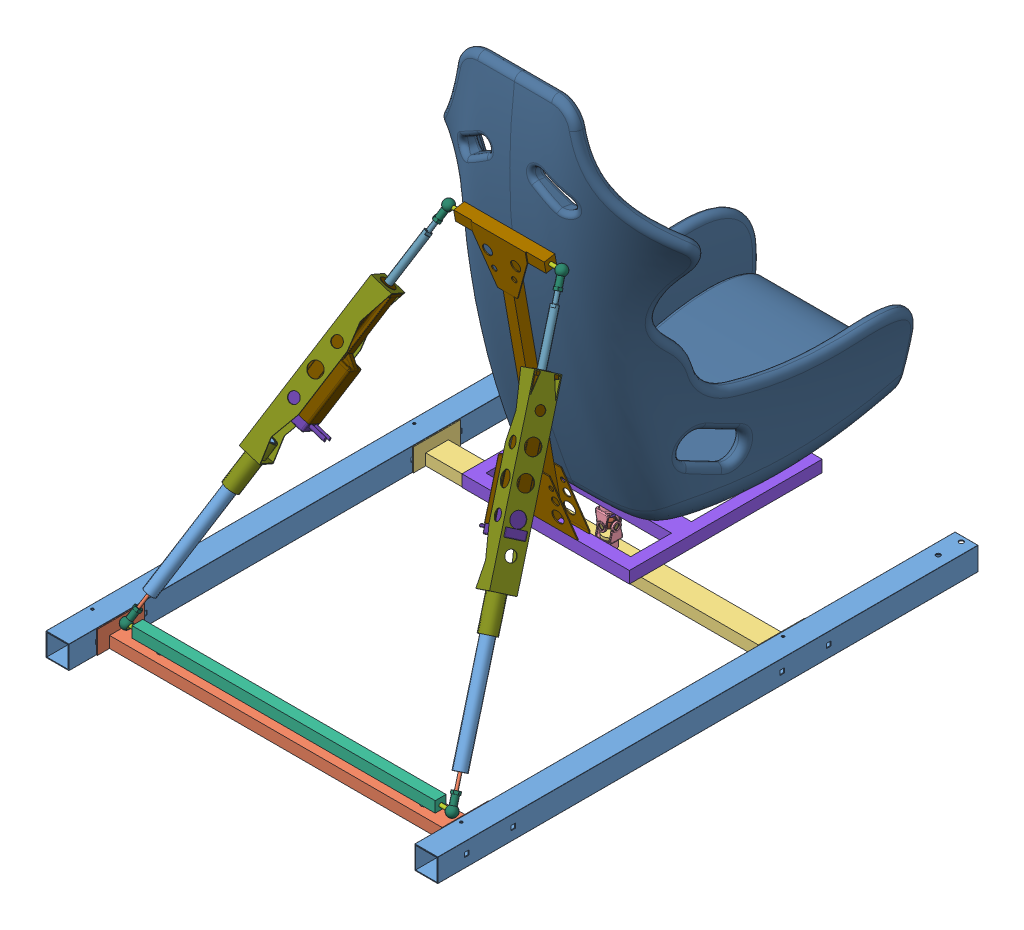
SolidWorks assembly simulateur, configuration Défaut. Lengths in mm.
Overall size (866 1108.83 1485.74).
50 component instances, 20 part files, 13 mates.
Components (placement in the parent):
- chassis-1: chassis [Défaut] at origin size (866 78.98 1194)
  - chassis_barre_laterale-1: chassis_barre_laterale [Défaut] at (-24.4445 -23.571 0) size (51 51 1194)
  - chassis_barre_laterale-2: chassis_barre_laterale [Défaut] at (-839.4445 -23.571 0) size (51 51 1194)
  - barre_arriere-1: barre_arriere [Défaut] at (-786.4445 -23.571 1056.3322) x (0 1 0) z (1 0 0) size (50 104 764)
  - barre_centrale-1: barre_centrale [Défaut] at (-26.4445 -23.571 407.634) x (0 1 0) z (-1 0 0) size (50 104 764)
  - fourche-1: fourche [Défaut] at (-406.4445 -20.721 382.634) x (0 0 1) z (-1 0 0) size (30.18 53.98 36.51)
  - plot-1: plot [Défaut] at (-696.9445 1.429 1081.4017) x (0 1 0) z (0 0 1) size (10 15 15)
  - plot-2: plot [Défaut] at (-115.9445 1.429 1081.4763) x (0 1 0) z (-0.196557 0 0.980492) size (10 15 15)
  - barre-1: barre [Défaut] at (-746.4445 35.429 1096.7272) x (0 0 -1) z (0 -1 0) size (24 670 24)
  - joint_rotule_male-1: joint_rotule_male [Défaut] at (-771.4445 21.1645 1084.3239) x (0 0.466315 -0.884619) z (1 0 0) size (20 20 35)
  - joint_rotule_male-2: joint_rotule_male [Défaut] at (-51.4445 21.1645 1084.3239) x (0 0.99969 0.0249) z (-1 0 0) size (20 20 35)
- siege-1: siege [Défaut] at (-246.4445 90.329 96.634) x (0 0 1) z (0 1 0) size (1024.11 731.48 1108.83)
  - support_siege_inferieur-1: support_siege_inferieur [Défaut] at origin size (426 370 52)
  - support_siege_arriere-1: support_siege_arriere [Défaut] at (424.1282 -171.5 26.7272) x (0.173648 0 0.984808) z (-0.984808 0 0.173648) size (636.1 200 32.48)
  - fourche-1: fourche [Défaut] at (286 -160 22.15) x (0 1 0) z (-1 0 0) size (30.18 53.98 36.51)
  - siege-1: siege [Défaut] at (-162.8445 -147.6332 -30.6502) x (-0.014699 -0.999786 -0.014541) z (-0.988338 0.016732 -0.151352) size (705.1 977.38 875.83)
  - joint_rotule_male-1: joint_rotule_male [Défaut] at (515.8074 -284.5 615.7706) x (-0.898781 0 0.438397) z (0 1 0) size (20 20 35)
  - joint_rotule_male-2: joint_rotule_male [Défaut] at (515.8074 -34.5 615.7706) x (0.795824 0 -0.605528) z (0 -1 0) size (20 20 35)
- joint_croix-1: joint_croix [Défaut] at (-406.4445 45.879 382.6338) x (0 0 -1) z (1 0 0) size (31.75 17.28 31.75)
  - croix-1: croix [Défaut] at origin size (28.57 12.7 28.57)
  - coussinet-1: coussinet [Défaut] at (-8.501 0 0) x (0 0.97948 0.20154) z (-1 0 0) size (12.7 12.7 3.97)
  - coussinet-2: coussinet [Défaut] at (-0.0002 0 -8.5008) x (0.94577 -0.324837 0) z (0 0 -1) size (12.7 12.7 3.97)
  - coussinet-3: coussinet [Défaut] at (-0.0002 0 8.5008) size (12.7 12.7 3.97)
  - coussinet-4: coussinet [Défaut] at (8.5006 0 0) x (0 -0.488169 -0.872749) z (1 0 0) size (12.7 12.7 3.97)
  - snapring-1: snapring [Défaut] at (15.4779 -0.0149 -0.2115) x (0 -0.997523 0.070347) z (1 0 0) size (14.29 14.21 0.79)
  - snapring-2: snapring [Défaut] at (-0.0002 0.212 -15.4781) size (14.29 14.21 0.79)
  - snapring-3: snapring [Défaut] at (-0.0002 0.212 15.4781) size (14.29 14.21 0.79)
  - snapring-4: snapring [Défaut] at (-15.4783 0.2076 -0.0428) x (0 -0.201908 -0.979404) z (1 0 0) size (14.29 14.21 0.79)
- tige_verin-1: tige_verin [Défaut] at (-606.3592 491.3214 760.4117) x (-0.960475 0.239444 -0.141964) z (0.27777 0.79108 -0.54501) size (25.18 26.83 230.5)
  - tige_verin-1: tige_verin [Défaut] at origin size (15 15 186.5)
  - joint_rotule_femelle-1: joint_rotule_femelle [Défaut] at (0 0 271.5) x (-0.954092 -0.299513 0) z (0 0 -1) size (19.49 22 44)
- verin-1: verin [Défaut] at (-700.8199 295.8158 874.9491) x (0.27777 0.79108 -0.54501) z (0.930808 -0.36194 -0.050958) size (715 50 102.68)
  - support_verin-1: support_verin [Défaut] at origin size (422 50 46)
  - corps_verin-1: corps_verin [Défaut] at (53.4998 119.4835 -2.1976) x (0 1 0) z (1 0 0) size (45 102.68 269)
    - RSA04-1: RSA04 [Défaut] at (-95.9835 24.6976 97.5002) size (44 102.68 87.5)
    - prt-SCN5-150-2: prt-SCN5-150 [Défaut] at (-96.4835 25.1976 97.5002) size (45 68.14 252)
  - extension_tige-1: extension_tige [Défaut] at (32 23 23) x (0 -0.760787 -0.649002) z (-1 0 0) size (26 26 320)
  - joint_rotule_femelle-1: joint_rotule_femelle [Défaut] at (-351 23 23) x (0 0.07072 0.997496) z (1 0 0) size (19.49 22 44)
  - tige_filetee-1: tige_filetee [Défaut] at (-172 23 23) x (0 -0.855363 -0.518028) z (0 0.518028 -0.855363) size (6 152 6)
- tige_verin-2: tige_verin [Défaut] at (-208.7297 490.577 760.9246) x (0.450435 0.603939 0.657546) z (-0.265985 0.793822 -0.5469) size (25.18 26.83 230.5)
  - tige_verin-1: tige_verin [Défaut] at origin size (15 15 186.5)
  - joint_rotule_femelle-1: joint_rotule_femelle [Défaut] at (0 0 271.5) x (-0.954092 -0.299513 0) z (0 0 -1) size (19.49 22 44)
- verin-2: verin [Défaut] at (-134.1225 319.573 915.8729) x (-0.265985 0.793822 -0.5469) z (-0.873086 -0.438873 -0.212396) size (715 50 102.68)
  - support_verin-1: support_verin [Défaut] at origin size (422 50 46)
  - corps_verin-1: corps_verin [Défaut] at (53.4998 119.4835 -2.1976) x (0 1 0) z (1 0 0) size (45 102.68 269)
    - RSA04-1: RSA04 [Défaut] at (-95.9835 24.6976 97.5002) size (44 102.68 87.5)
    - prt-SCN5-150-2: prt-SCN5-150 [Défaut] at (-96.4835 25.1976 97.5002) size (45 68.14 252)
  - extension_tige-1: extension_tige [Défaut] at (32 23 23) x (0 -0.760787 -0.649002) z (-1 0 0) size (26 26 320)
  - joint_rotule_femelle-1: joint_rotule_femelle [Défaut] at (-351 23 23) x (0 0.07072 0.997496) z (1 0 0) size (19.49 22 44)
  - tige_filetee-1: tige_filetee [Défaut] at (-172 23 23) x (0 -0.855363 -0.518028) z (0 0.518028 -0.855363) size (6 152 6)
Mates (geometry in assembly coordinates):
- Coaxiale1: concentric anti-aligned: cylinder of chassis-1/fourche-1; cylinder of joint_croix-1/coussinet-2
- Coaxiale2: concentric anti-aligned: cylinder of chassis-1/fourche-1; cylinder of joint_croix-1/coussinet-2
- Coïncidente1: coincident anti-aligned: plane of chassis-1/fourche-1 through (-422.3195 45.879 382.634) normal (1 0 0); plane of joint_croix-1/snapring-2 through (-422.3195 45.879 382.634) normal (-1 0 0)
- Coaxiale3: concentric anti-aligned: cylinder of siege-1/fourche-1; cylinder of joint_croix-1/coussinet-1
- Coïncidente2: coincident anti-aligned: plane of siege-1/fourche-1 through (-406.4445 45.879 398.509) normal (0 0 -1); plane of joint_croix-1/snapring-4 through (-406.4445 45.879 398.509) normal (0 0 1)
- Coaxiale4: concentric anti-aligned: cylinder of tige_verin-1/tige_verin-1; cylinder of verin-1/corps_verin-1/prt-SCN5-150-2
- Coaxiale5: concentric: sphere of siege-1/joint_rotule_male-1; sphere of tige_verin-1/joint_rotule_femelle-1
- Coaxiale6: concentric: sphere of siege-1/joint_rotule_male-2; sphere of tige_verin-2/joint_rotule_femelle-1
- Coaxiale7: concentric anti-aligned: cylinder of tige_verin-2/tige_verin-1; cylinder of verin-2/corps_verin-1/prt-SCN5-150-2
- Coaxiale8: concentric: sphere of chassis-1/joint_rotule_male-1; sphere of verin-1/joint_rotule_femelle-1
- Coaxiale9: concentric: sphere of chassis-1/joint_rotule_male-2; sphere of verin-2/joint_rotule_femelle-1
- Parallèle2: parallel: plane of chassis-1/barre_centrale-1 through (-786.4445 1.429 407.634) normal (0 1 0); line of siege-1/support_siege_inferieur-1
- Parallèle3: parallel anti-aligned: plane of chassis-1/chassis_barre_laterale-1 through (-24.4445 27.429 1194) normal (0 1 0); plane of siege-1/support_siege_inferieur-1 through (-221.4445 90.329 96.634) normal (0 -1 0)
